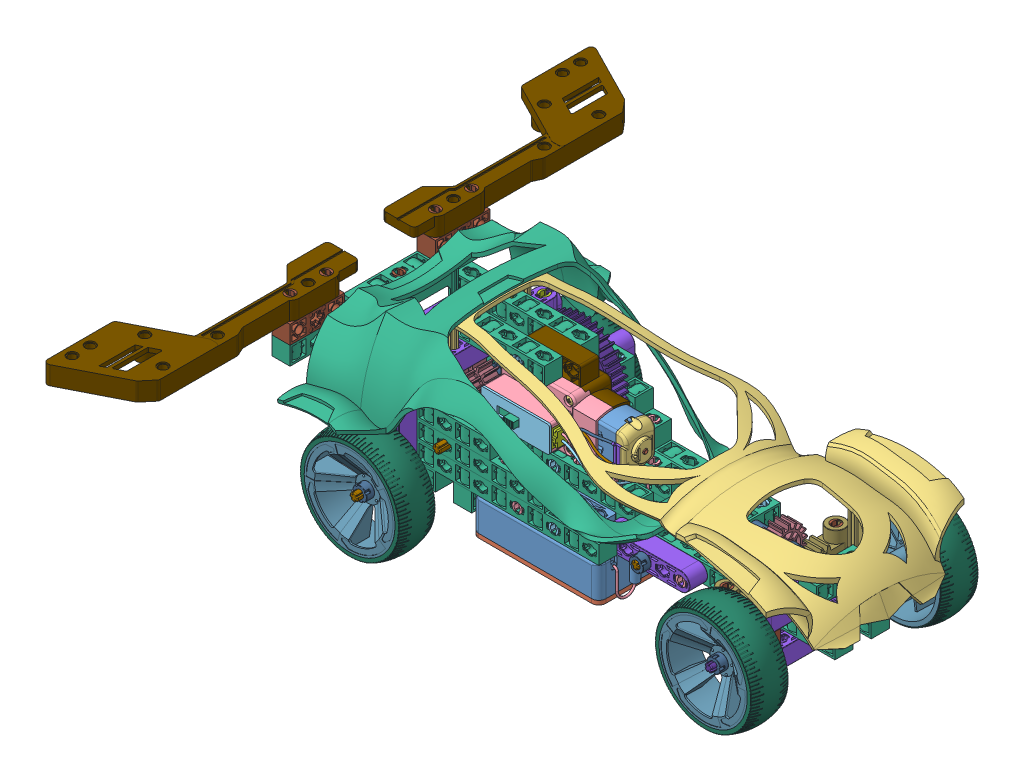
SolidWorks assembly Montagem Carro completo 2, configuration Default. Lengths in mm.
Overall size (284.9 101.61 271.25).
192 component instances, 42 part files, 28 mates.
Components (placement in the parent):
- Subconjunto Vigas traseiras-1: Subconjunto Vigas traseiras [Default] at (83.2647 104.1933 53.5414) x (-1 0 0) z (0 0 1) size (139.81 64.5 81)
  - Subconjunto caixa pilhas-1: Subconjunto caixa pilhas [Default] at (12.3707 2.7009 -5.3452) size (69.81 28.5 63)
    - Caixa das pilhas-1: Caixa das pilhas [Default] at (12.7241 32.9375 62.5857) size (69.5 28.5 63)
    - Tampa compartimento das pilhas-1: Tampa compartimento das pilhas [Default] at (12.7241 42.9375 62.5857) x (0 0 1) z (1 0 0) size (63 4 69.5)
    - pan head cross recess screw_iso-4: pan head cross recess screw_iso [ISO 7045 - M2 x 6 - Z - 6N] at (-20.7759 42.7775 62.5857) x (0 -1 0) z (0.784317 0 0.62036) size (7.57 4 4)
  - Pino Paralelo-2: Pino Paralelo [Default] at (34.0948 23.1383 79.7405) x (-1 0 0) z (0 -1 0) size (6 18 4.58)
  - Pino Triplo Longo-1: Pino Triplo Longo [Default] at (16.0948 23.1383 75.2405) x (1 0 0) z (0 -1 0) size (6 27 4.58)
  - Viga alternada-1: Viga alternada [Viga alternada de 15] at (61.0948 23.1383 84.2405) x (1 0 0) z (0 1 0) size (135 9 9)
  - Pino Triplo Longo-2: Pino Triplo Longo [Default] at (97.0948 23.1383 84.2405) size (6 27 4.58)
  - Pino Triplo Longo-3: Pino Triplo Longo [Default] at (79.0948 23.1383 84.2405) size (6 27 4.58)
  - Viga alternada-2: Viga alternada [Viga alternada de 3] at (88.0948 32.1383 84.2405) size (27 9 9)
  - Pino Perpendicular-1: Pino Perpendicular [Default] at (61.0948 27.6383 84.2405) x (0 0 -1) z (1 0 0) size (6 18 6)
  - Viga alternada-3: Viga alternada [Viga alternada de 11] at (70.0948 14.1383 84.2405) size (99 9 9)
  - Pino Paralelo-4: Pino Paralelo [Default] at (43.0948 18.6383 84.2405) size (6 18 4.58)
  - Pino Paralelo-5: Pino Paralelo [Default] at (25.0948 18.6383 84.2405) size (6 18 4.58)
  - Pino Paralelo-6: Pino Paralelo [Default] at (34.0948 23.1383 34.7405) x (-1 0 0) z (0 1 0) size (6 18 4.58)
  - Pino Triplo Longo-4: Pino Triplo Longo [Default] at (16.0948 23.1383 39.2405) x (1 0 0) z (0 1 0) size (6 27 4.58)
  - Viga alternada-4: Viga alternada [Viga alternada de 15] at (61.0948 23.1383 30.2405) x (1 0 0) z (0 -1 0) size (135 9 9)
  - Pino Triplo Longo-5: Pino Triplo Longo [Default] at (97.0948 23.1383 30.2405) size (6 27 4.58)
  - Pino Triplo Longo-6: Pino Triplo Longo [Default] at (79.0948 23.1383 30.2405) size (6 27 4.58)
  - Viga alternada-5: Viga alternada [Viga alternada de 3] at (88.0948 32.1383 30.2405) size (27 9 9)
  - Pino Perpendicular-2: Pino Perpendicular [Default] at (61.0948 27.6383 30.2405) x (0 0 1) z (-1 0 0) size (6 18 6)
  - Viga alternada-6: Viga alternada [Viga alternada de 11] at (70.0948 14.1383 30.2405) size (99 9 9)
  - Pino Paralelo-7: Pino Paralelo [Default] at (25.0948 18.6383 30.2405) size (6 18 4.58)
  - Pino Perpendicular-3: Pino Perpendicular [Default] at (115.0948 27.6383 84.2405) x (0 0 1) z (-1 0 0) size (6 18 6)
  - Pino Perpendicular-4: Pino Perpendicular [Default] at (115.0948 9.6383 84.2405) size (6 18 6)
  - Pino Perpendicular-5: Pino Perpendicular [Default] at (115.0948 27.6383 30.2405) x (0 0 -1) z (1 0 0) size (6 18 6)
  - Pino Perpendicular-6: Pino Perpendicular [Default] at (115.0948 9.6383 30.2405) size (6 18 6)
  - Viga alternada-7: Viga alternada [Viga alternada de 7] at (61.0948 32.1383 57.2405) x (0 0 -1) z (1 0 0) size (63 9 9)
  - Viga plana-1: Viga plana [Viga plana de 7] at (115.0948 32.1383 57.2405) x (0 0 1) z (-1 0 0) size (63 9 9)
  - Viga plana-2: Viga plana [Viga plana de 7] at (115.0948 5.1383 57.2405) x (0 0 1) z (1 0 0) size (63 9 9)
  - Pino Paralelo-8: Pino Paralelo [Default] at (61.0948 9.6383 84.2405) size (6 18 4.58)
  - Viga alternada-8: Viga alternada [Viga alternada de 7] at (79.0948 5.1383 84.2405) x (1 0 0) z (0 -1 0) size (63 9 9)
  - Pino Paralelo-9: Pino Paralelo [Default] at (97.0948 0.6383 84.2405) x (-1 0 0) z (0 0 -1) size (6 18 4.58)
  - Pino Triplo Longo-7: Pino Triplo Longo [Default] at (79.0948 -3.8617 84.2405) x (-1 0 0) z (0 0 -1) size (6 27 4.58)
  - Viga alternada-9: Viga alternada [Viga alternada de 5] at (97.0948 -3.8617 84.2405) size (45 9 9)
  - Viga alternada-10: Viga alternada [Viga alternada de 9] at (70.0948 5.1383 30.2405) x (1 0 0) z (0 1 0) size (81 9 9)
  - Viga alternada-11: Viga alternada [Viga alternada de 9] at (79.0948 -3.8617 30.2405) size (81 9 9)
  - Pino Triplo Longo-8: Pino Triplo Longo [Default] at (61.0948 5.1383 30.2405) x (-1 0 0) z (0 0 1) size (6 27 4.58)
  - Pino Triplo Longo-9: Pino Triplo Longo [Default] at (43.0948 5.1383 30.2405) x (1 0 0) z (0 0 -1) size (6 27 4.58)
  - Pino Paralelo-10: Pino Paralelo [Default] at (97.0948 0.6383 30.2405) size (6 18 4.58)
  - Pino Perpendicular-8: Pino Perpendicular [Default] at (79.0948 -8.3617 30.2405) size (6 18 6)
  - Viga plana-3: Viga plana [Viga plana de 5] at (88.0948 14.1383 93.2405) x (0 -1 0) z (-1 0 0) size (45 9 9)
  - Pino Perpendicular-9: Pino Perpendicular [Default] at (88.0948 -3.8617 88.7405) x (0 -1 0) z (-1 0 0) size (6 18 6)
  - Viga plana-5: Viga plana [Viga plana de 7] at (79.0948 -12.8617 57.2405) x (0 0 1) z (-1 0 0) size (63 9 9)
  - Viga alternada-12: Viga alternada [Viga alternada de 3 (Preta)] at (106.0948 5.1383 75.2405) x (0 -1 0) z (1 0 0) size (27 9 9)
  - Pino Perpendicular-11: Pino Perpendicular [Default] at (106.0948 -3.8617 79.7405) x (0 -1 0) z (1 0 0) size (6 18 6)
  - Pino Perpendicular-12: Pino Perpendicular [Default] at (106.0948 14.1383 79.7405) x (0 -1 0) z (1 0 0) size (6 18 6)
  - Pino Perpendicular-13: Pino Perpendicular [Default] at (88.0948 -3.8617 25.7405) x (0 -1 0) z (1 0 0) size (6 18 6)
  - Viga plana-6: Viga plana [Viga plana de 5] at (88.0948 14.1383 21.2405) x (0 -1 0) z (1 0 0) size (45 9 9)
  - Pino Perpendicular-15: Pino Perpendicular [Default] at (106.0948 -3.8617 34.7405) x (0 -1 0) z (-1 0 0) size (6 18 6)
  - Viga alternada-13: Viga alternada [Viga alternada de 3 (Preta)] at (106.0948 5.1383 39.2405) x (0 -1 0) z (-1 0 0) size (27 9 9)
  - Pino Perpendicular-16: Pino Perpendicular [Default] at (106.0948 14.1383 34.7405) x (0 -1 0) z (-1 0 0) size (6 18 6)
  - Viga plana-7: Viga plana [Viga plana de 3] at (52.0948 5.1383 21.2405) x (0 1 0) z (-1 0 0) size (27 9 9)
  - Pino Perpendicular-17: Pino Perpendicular [Default] at (52.0948 14.1383 25.7405) x (0 1 0) z (-1 0 0) size (6 18 6)
  - Pino Perpendicular-18: Pino Perpendicular [Default] at (52.0948 5.1383 25.7405) x (0 1 0) z (-1 0 0) size (6 18 6)
  - Pino Perpendicular-19: Pino Perpendicular [Default] at (88.0948 23.1383 88.7405) x (1 0 0) z (0 1 0) size (6 18 6)
  - Pino Perpendicular-20: Pino Perpendicular [Default] at (88.0948 23.1383 25.7405) x (1 0 0) z (0 -1 0) size (6 18 6)
- Subconjunto direção-1: Subconjunto direção [Default] at (103.1154 2.655 4.4947) size (149.73 73.54 113.05) (flexible)
  - Viga alternada-1: Viga alternada [Viga alternada de 15] at (18.0545 78.4 115.2872) size (135 9 9)
  - Viga alternada-2: Viga alternada [Viga alternada de 15] at (18.0545 78.4 97.2872) size (135 9 9)
  - Viga plana-2: Viga plana [Viga plana de 5] at (0.0545 78.4 124.2872) x (1 0 0) z (0 1 0) size (45 9 9)
  - Pino Paralelo-1: Pino Paralelo [Default] at (18.0545 78.4 119.7872) x (1 0 0) z (0 1 0) size (6 18 4.58)
  - Veio-1: Veio [Veio no meio] at (0.0545 78.4 79.2872) x (0.200907 0.97961 0) z (0 0 1) size (4 4 54)
  - Freio-1: Freio [Freio Pequeno] at (0.0545 78.4 132.7872) x (0.97961 -0.200907 0) z (0 0 -1) size (7 7 4.02)
  - Viga plana-3: Viga plana [Viga plana de 3] at (0.0545 78.4 106.2872) x (1 0 0) z (0 -1 0) size (27 9 9)
  - Viga plana-4: Viga plana [Viga plana de 5] at (0.0545 78.4 88.2872) x (-1 0 0) z (0 1 0) size (45 9 9)
  - Freio-2: Freio [Freio Pequeno] at (0.0545 78.4 79.7872) x (-0.97961 0.200907 0) z (0 0 1) size (7 7 4.02)
  - Pino Paralelo-2: Pino Paralelo [Default] at (18.0545 78.4 92.7872) x (1 0 0) z (0 1 0) size (6 18 4.58)
  - Viga plana-5: Viga plana [Viga plana de 3] at (27.0545 87.4 106.2872) x (0 0 1) z (-1 0 0) size (27 9 9)
  - Pino Triplo Longo-1: Pino Triplo Longo [Default] at (27.0545 87.4 97.2872) x (0 0 1) z (-1 0 0) size (6 27 4.58)
  - Pino Triplo Longo-3: Pino Triplo Longo [Default] at (27.0545 87.4 115.2872) x (0 0 1) z (-1 0 0) size (6 27 4.58)
  - Viga alternada-3: Viga alternada [Viga alternada de 3] at (27.0545 96.4 106.2872) x (0 0 1) z (-1 0 0) size (27 9 9)
  - Pino Triplo Longo-4: Pino Triplo Longo [Default] at (63.0545 78.4 97.2872) size (6 27 4.58)
  - Pino Triplo Longo-5: Pino Triplo Longo [Default] at (63.0545 78.4 115.2872) size (6 27 4.58)
  - Viga plana-6: Viga plana [Viga plana de 7] at (63.0545 69.4 106.2872) x (0 0 -1) z (1 0 0) size (63 9 9)
  - Viga com pinos-1: Viga com pinos [Viga com pinos (Cinzenta)] at (54.0581 78.4 79.0329) x (0.999601 0 0.02826) z (-0.02826 0 0.999601) size (27 27 9)
  - Viga com pinos-2: Viga com pinos [Viga com pinos (Cinzenta)] at (54.0581 78.4 133.0329) x (0.999601 0 0.02826) z (-0.02826 0 0.999601) size (27 27 9)
  - Haste dentada-2: Haste dentada [Default] at (45.0617 85.9 105.7785) x (0 0 1) z (-1 0 0) size (63 9 9)
  - Freio-4: Freio [Freio Pequeno] at (62.8143 78.4 141.7838) x (0.706725 0.707206 0.01998) z (0.02826 0 -0.999601) size (7 7 4.02)
  - Pino Paralelo-3: Pino Paralelo [Default] at (81.0545 82.9 115.2872) size (6 18 4.58)
  - Viga plana-7: Viga plana [Viga em L] at (72.0545 87.4 115.2872) size (27 9 27)
  - Freio-6: Freio [Freio Pequeno] at (63.2947 78.4 70.7906) x (-0.609265 0.79278 -0.017224) z (-0.02826 0 0.999601) size (7 7 4.02)
  - Pino Paralelo-4: Pino Paralelo [Default] at (81.0545 82.9 97.2872) size (6 18 4.58)
  - Viga plana-8: Viga plana [Viga em L] at (72.0545 87.4 97.2872) x (1 0 0) z (0 0 -1) size (27 9 27)
  - Pino Perpendicular-2: Pino Perpendicular [Default] at (72.0545 91.9 115.2872) x (0 0 1) z (-1 0 0) size (6 18 6)
  - Pino Perpendicular-3: Pino Perpendicular [Default] at (72.0545 91.9 97.2872) x (0 0 1) z (-1 0 0) size (6 18 6)
  - Viga alternada-4: Viga alternada [Viga alternada de 3] at (72.0545 96.4 106.2872) x (0 0 1) z (-1 0 0) size (27 9 9)
  - Veio-4: Veio [Veio Direção] at (81.0545 96.4 106.2872) x (0 0.998403 0.056489) z (-1 0 0) size (4 4 72)
  - Freio-7: Freio [Frei Grande] at (40.5545 96.4 106.2872) x (0 -0.998403 -0.056489) z (-1 0 0) size (7 7 9.02)
  - Roda Dentada 18-1: Roda Dentada 18 [Default] at (45.0545 96.4 106.2872) x (0 -0.998403 -0.056489) z (1 0 0) size (19.8 20 9)
  - Freio-8: Freio [Freio Pequeno] at (18.5545 96.4 106.2872) x (0 -0.056489 0.998403) z (1 0 0) size (7 7 4.02)
  - Freio-10: Freio [Freio Pequeno] at (80.5545 96.4 106.2872) x (0 0.056489 -0.998403) z (-1 0 0) size (7 7 4.02)
  - Subconjunto Rodas-1: Subconjunto Rodas [Default] at (112.9706 74.3889 157.6368) x (0.02826 0 -0.999601) z (-0.706923 0.707008 -0.019985) size (20 52.21 52.21)
    - Jante (centro arredondado)-1: Jante (centro arredondado) [Default] at (3.4293 32.9268 38.6094) size (20 48 48)
    - Pneu com detalhes-1: Pneu com detalhes [Default] at (3.4293 32.9268 38.6094) x (1 0 0) z (0 0.004073 0.999992) size (18 52 52)
  - Volante-3: Volante [Default] at (18.5545 96.4 106.2872) x (0 -0.056489 0.998403) z (-1 0 0) size (26 17 5.56)
  - Subconjunto Rodas-2: Subconjunto Rodas [Default] at (114.3601 75.829 57.7993) x (-0.02826 0 0.999601) z (-0.792463 -0.609508 -0.022404) size (20 52.21 52.21)
    - Jante (centro arredondado)-1: Jante (centro arredondado) [Default] at (3.4293 32.9268 38.6094) size (20 48 48)
    - Pneu com detalhes-1: Pneu com detalhes [Default] at (3.4293 32.9268 38.6094) x (1 0 0) z (0 0.004073 0.999992) size (18 52 52)
  - Freio-11: Freio [Freio Pequeno] at (62.3904 78.4 156.7778) x (0.706725 0.707206 0.01998) z (0.02826 0 -0.999601) size (7 7 4.02)
  - Freio-12: Freio [Freio Pequeno] at (63.7186 78.4 55.7966) x (0.609265 -0.79278 0.017224) z (-0.02826 0 0.999601) size (7 7 4.02)
  - Veio de direção-1: Veio de direção [Default] at (62.9414 78.4 137.2856) x (0.706923 -0.707008 0.019985) z (-0.706725 -0.707206 -0.01998) size (5 31 5)
  - Veio de direção-2: Veio de direção [Default] at (63.1675 78.4 75.2888) x (-0.792463 -0.609508 -0.022404) z (0.609265 -0.79278 0.017224) size (5 31 5)
  - Freio-13: Freio [Freio Pequeno] at (53.5545 96.4 106.2872) x (0 0.056489 -0.998403) z (-1 0 0) size (7 7 4.02)
- Subconjunto motor (+ vigas pinos engrenagem)-1: Subconjunto motor (+ vigas pinos engrenagem) [Default] at (30.8311 154.6885 76.1191) x (1 0 0) z (0 -1 0) size (90 66.4 56.53) (flexible)
  - Subconjunto motor-1: Subconjunto motor [Default] at (-5.6196 12.0173 6.5738) size (65.27 37.9 45) (flexible)
    - Caixa motor superior-1: Caixa motor superior [Default] at (12.9584 20.6455 40.0597) size (48 14.5 45)
    - Carcaça-1: Carcaça [Default] at (41.4584 25.1455 40.0597) size (21 15 20.02)
    - Veio rotor-1: Veio rotor [Default] at (40.9584 25.1455 40.0597) x (1 0 0) z (0 -0.841943 0.539566) size (36 2 2)
    - Tampa-1: Tampa [Default] at (52.4584 25.1455 40.0597) x (-1 0 0) z (0 0 -1) size (10.02 16 20.34)
    - Caixa motor inferior-1: Caixa motor inferior [Default] at (12.9584 33.1455 40.0597) x (1 0 0) z (0 0 -1) size (48 22 27)
    - Capa interruptor-1: Capa interruptor [Default] at (12.9584 43.1455 40.0597) size (34 8 13)
    - Interruptor-1: Interruptor [Default] at (12.4584 42.1455 40.0597) size (18 5 6)
    - pan head cross recess screw_iso-1: pan head cross recess screw_iso [ISO 7045 - M2 x 12 - Z - 12N] at (-2.5416 32.9855 50.5597) x (0 -1 0) z (0 0 1) size (13.57 4 4)
    - pan head cross recess screw_iso-2: pan head cross recess screw_iso [ISO 7045 - M2 x 12 - Z - 12N] at (28.4584 32.9855 50.5597) x (0 -1 0) z (-0.094826 0 0.995494) size (13.57 4 4)
    - pan head cross recess screw_iso-3: pan head cross recess screw_iso [ISO 7045 - M2 x 12 - Z - 12N] at (28.4584 32.9855 29.5597) x (0 -1 0) z (0 0 1) size (13.57 4 4)
    - pan head cross recess screw_iso-4: pan head cross recess screw_iso [ISO 7045 - M2 x 12 - Z - 12N] at (-2.5416 32.9855 29.5597) x (0 -1 0) z (0 0 1) size (13.57 4 4)
    - Ficha-1: Ficha [Default] at (31.9584 39.6455 40.0597) x (-1 0 0) z (0 0 -1) size (9 7 9)
    - Terminais motor-1: Terminais motor [Default] at (52.9584 32.7705 40.0597) size (3 2.95 10.2)
    - Part14^Subconjunto motor-1: Part14^Subconjunto motor [Default] at (27.9584 33.1455 40.0597) x (0 0 1) z (1 0 0) size (7.51 1.91 24.5) (virtual)
    - Part15^Subconjunto motor-1: Part15^Subconjunto motor [Default] at (27.9584 33.1455 40.0597) x (0 0 1) z (1 0 0) size (7.38 2.7 24.5) (virtual)
    - Veios interiores motor-1: Veios interiores motor [Veio cilindro menor] at (16.9584 22.6455 40.0597) x (0 1 0) z (0.959634 0 0.281251) size (19 2 2)
    - Veios interiores motor-2: Veios interiores motor [Veio cilindro maior] at (5.9584 24.6955 40.0597) x (0 1 0) z (0 0 1) size (14.9 2 2)
    - Engrenagem veio rotor-1: Engrenagem veio rotor [Default] at (25.6584 25.1455 40.0597) x (0 0.753099 0.657907) z (0 -0.657907 0.753099) size (6 5.02 6.03)
    - 1º Engrenagem-1: 1º Engrenagem [Default] at (16.9584 29.7455 40.0597) x (0.999602 0 0.028216) z (0.028216 0 -0.999602) size (17.01 7.3 17.01)
    - 2º e 3º Engrenagem-1: 2º e 3º Engrenagem [Default] at (5.9584 25.7455 40.0597) x (-0.546136 0 0.837696) z (0.837696 0 0.546136) size (17.4 6.4 17.38)
    - 2º e 3º Engrenagem-2: 2º e 3º Engrenagem [Default] at (16.9584 22.0455 40.0597) x (-0.894705 0 0.446658) z (0.446658 0 0.894705) size (17.4 6.4 17.38)
    - 4º Engrenagem-1: 4º Engrenagem [Default] at (5.9584 19.7455 40.0597) x (-0.755862 0 0.65473) z (0.65473 0 0.755862) size (17.4 3 17.4)
    - Engrenagem saída do motor-1: Engrenagem saída do motor [Default] at (5.9584 18.2455 40.0597) x (-0.983161 0 -0.182739) z (-0.182739 0 0.983161) size (11.75 9 11.02)
  - Pino Triplo Longo-1: Pino Triplo Longo [Default] at (0.3388 34.6628 64.6335) x (-1 0 0) z (0 0 1) size (6 27 4.58)
  - Pino Triplo Longo-2: Pino Triplo Longo [Default] at (18.3388 34.6628 64.6335) x (-1 0 0) z (0 0 1) size (6 27 4.58)
  - Pino Triplo Longo-3: Pino Triplo Longo [Default] at (0.3388 34.6628 28.6335) size (6 27 4.58)
  - Viga alternada-1: Viga alternada [Viga alternada de 5] at (-8.6612 43.6628 28.6335) x (1 0 0) z (0 -1 0) size (45 9 9)
  - Viga alternada-2: Viga alternada [Viga alternada de 7] at (27.3388 43.6628 64.6335) size (63 9 9)
  - Pino Perpendicular-1: Pino Perpendicular [Default] at (-26.6612 43.6628 33.1335) x (0 -1 0) z (1 0 0) size (6 18 6)
  - Pino Paralelo-1: Pino Paralelo [Default] at (45.3388 43.6628 69.1335) x (1 0 0) z (0 1 0) size (6 18 4.58)
  - Pino Paralelo-2: Pino Paralelo [Default] at (27.3388 43.6628 69.1335) x (1 0 0) z (0 1 0) size (6 18 4.58)
  - Viga alternada-3: Viga alternada [Viga alternada de 5] at (-8.6612 25.6628 28.6335) x (1 0 0) z (0 -1 0) size (45 9 9)
  - Pino Perpendicular-2: Pino Perpendicular [Default] at (-26.6612 25.6628 33.1335) x (0 1 0) z (-1 0 0) size (6 18 6)
  - Viga alternada-4: Viga alternada [Viga alternada de 7] at (27.3388 25.6628 64.6335) x (1 0 0) z (0 0 -1) size (63 9 9)
  - Pino Paralelo-3: Pino Paralelo [Default] at (27.3388 25.6628 69.1335) x (1 0 0) z (0 1 0) size (6 18 4.58)
  - Pino Paralelo-4: Pino Paralelo [Default] at (45.3388 25.6628 69.1335) x (1 0 0) z (0 1 0) size (6 18 4.58)
  - Veio-1: Veio [Veio do motor] at (0.3388 -7.2372 46.6335) x (-0.983161 0 -0.182739) z (0 1 0) size (4 4 36)
  - Roda Dentada 41-1: Roda Dentada 41 [Default] at (0.3388 17.6628 46.6335) x (-0.983161 0 -0.182739) z (0 1 0) size (42.99 42.96 10)
- Subconjunto Aileron-1: Subconjunto Aileron [Default] at (26.7336 51.1658 81.6411) x (0 0 1) z (-1 0 0) size (271.25 45.1 54)
  - Viga alternada-1: Viga alternada [Viga alternada de 11 (Preta)] at (29.1408 56.8892 76.5637) size (99 9 9)
  - Viga com pinos-2: Viga com pinos [Viga com pinos (Cinzenta)] at (65.1408 65.8892 76.5637) size (27 27 9)
  - Viga com pinos-3: Viga com pinos [Viga com pinos (Branca)] at (29.1408 47.8892 76.5637) size (27 27 9)
  - Viga alternada-2: Viga alternada [Viga alternada de 3 (Preta)] at (38.1408 38.8892 67.5637) x (0 0 -1) z (-1 0 0) size (27 9 9)
  - Pino Perpendicular-1: Pino Perpendicular [Default] at (38.1408 43.3892 58.5637) x (-1 0 0) z (0 0 1) size (6 18 6)
  - Asa-3: Asa [Asa Direita] at (65.1408 79.3892 76.5637) x (-1 0 0) z (0 0 1) size (122.12 9.1 36.5)
  - Viga com pinos-6: Viga com pinos [Viga com pinos (Cinzenta)] at (-6.8592 65.8892 76.5637) x (-1 0 0) z (0 0 -1) size (27 27 9)
  - Viga alternada-4: Viga alternada [Viga alternada de 3 (Preta)] at (20.1408 38.8892 67.5637) x (0 0 -1) z (-1 0 0) size (27 9 9)
  - Asa-5: Asa [Asa Esquerda] at (38.1408 79.3892 76.5637) x (-1 0 0) z (0 0 1) size (122.12 9.1 36.5)
  - Pino Perpendicular-3: Pino Perpendicular [Default] at (20.1408 43.3892 58.5637) x (1 0 0) z (0 0 -1) size (6 18 6)
- Subconjunto 1º aumento-1: Subconjunto 1º aumento [Default] at (10.181 89.2697 93.6538) x (-0.111043 -0.993816 0) z (0 0 1) size (27.87 28 72) (flexible)
  - Veio-1: Veio [Veio Direção] at (-1.1123 2.8833 -19.3719) size (4 4 72)
  - Roda Dentada 10-1: Roda Dentada 10 [Default] at (-1.1123 2.8833 -0.8719) size (11.6 12 9)
  - Roda Dentada 26-2: Roda Dentada 26 [Default] at (-1.1123 2.8833 34.1281) size (27.87 28 9)
  - Freio-1: Freio [Freio Pequeno] at (-1.1123 2.8833 12.6281) size (7 7 4.02)
  - Freio-2: Freio [Freio Pequeno] at (-1.1123 2.8833 20.6281) x (1 0 0) z (0 0 -1) size (7 7 4.02)
  - Freio-3: Freio [Frei Grande] at (-1.1123 2.8833 20.6281) size (7 7 9.02)
  - Freio-4: Freio [Frei Grande] at (-1.1123 2.8833 12.6281) x (-1 0 0) z (0 0 -1) size (7 7 9.02)
- Subconjunto 2º aumento-2: Subconjunto 2º aumento [Default] at (-5.1688 93.2831 88.3144) x (-0.561891 0.827211 0) z (0 0 1) size (19.8 20 81) (flexible)
  - Veio-1: Veio [Veio 2º aumento] at (-2.8606 1.5336 -17.5324) size (4 4 81)
  - Roda Dentada 10-1: Roda Dentada 10 [Default] at (-2.8606 1.5336 40.4676) size (11.6 12 9)
  - Freio-1: Freio [Freio Pequeno] at (-2.8606 1.5336 35.9676) x (-1 0 0) z (0 0 -1) size (7 7 4.02)
  - Roda Dentada 18-1: Roda Dentada 18 [Default] at (-2.8606 1.5336 27.4676) size (19.8 20 9)
  - Roda Dentada 18-2: Roda Dentada 18 [Default] at (-2.8606 1.5336 18.4676) size (19.8 20 9)
  - Freio-2: Freio [Freio Pequeno] at (-2.8606 1.5336 9.9676) size (7 7 4.02)
  - Freio-4: Freio [Frei Grande] at (-2.8606 1.5336 9.9676) x (-1 0 0) z (0 0 -1) size (7 7 9.02)
- Subconjunto Veio final-1: Subconjunto Veio final [Default] at (50.8445 119.9269 8.5329) x (-0.969875 0.243603 0) z (0 0 1) size (52.21 52.21 121) (flexible)
  - Veio-1: Veio [Veio Final] at (42.3357 59.9923 43.749) size (4 4 117)
  - Roda Dentada 18-1: Roda Dentada 18 [Default] at (42.3357 59.9923 106.749) size (19.8 20 9)
  - Roda Dentada 18-2: Roda Dentada 18 [Default] at (42.3357 59.9923 97.749) size (19.8 20 9)
  - Freio-1: Freio [Frei Grande] at (42.3357 59.9923 89.249) x (-1 0 0) z (0 0 -1) size (7 7 9.02)
  - Freio-2: Freio [Frei Grande] at (42.3357 59.9923 115.249) size (7 7 9.02)
  - Freio-3: Freio [Freio Pequeno] at (42.3357 59.9923 89.249) size (7 7 4.02)
  - Freio-4: Freio [Freio Pequeno] at (42.3357 59.9923 115.249) x (-1 0 0) z (0 0 -1) size (7 7 4.02)
  - Freio-5: Freio [Freio Pequeno] at (42.3357 59.9923 46.749) size (7 7 4.02)
  - Subconjunto Rodas-1: Subconjunto Rodas [Default] at (80.9451 27.0654 47.3198) x (0 0 1) z (-1 0 0) size (20 52.21 52.21)
    - Jante (centro arredondado)-1: Jante (centro arredondado) [Default] at (3.4293 32.9268 38.6094) size (20 48 48)
    - Pneu com detalhes-1: Pneu com detalhes [Default] at (3.4293 32.9268 38.6094) x (1 0 0) z (0 0.004073 0.999992) size (18 52 52)
  - Subconjunto Rodas-3: Subconjunto Rodas [Default] at (3.7263 27.0654 157.1783) x (0 0 -1) z (1 0 0) size (20 52.21 52.21)
    - Jante (centro arredondado)-1: Jante (centro arredondado) [Default] at (3.4293 32.9268 38.6094) size (20 48 48)
    - Pneu com detalhes-1: Pneu com detalhes [Default] at (3.4293 32.9268 38.6094) x (1 0 0) z (0 0.004073 0.999992) size (18 52 52)
  - Freio-9: Freio [Freio Pequeno] at (42.3357 59.9923 157.749) x (-1 0 0) z (0 0 -1) size (7 7 4.02)
- Carroçaria parte comprida-1: Carroçaria parte comprida [Default] at (4.1699 113.3206 110.782) size (202.22 51.99 99.26)
- Part2^Montagem Carro completo-1: Part2^Montagem Carro completo [Default] at (88.3699 68.555 110.782) x (0 0 1) z (1 0 0) size (23.89 52.5 35.5)
- Part3^Montagem Carro completo-1: Part3^Montagem Carro completo [Default] at (56.1699 108.055 127.782) x (0 1 0) z (1 0 0) size (49.52 46.13 35.5)
- Carroçaria parte curta-1: Carroçaria parte curta [Default] at (4.1699 137.8495 110.782) size (140.2 59.94 138.22)
Mates (geometry in assembly coordinates):
- Concentric31: concentric aligned: cylinder of Subconjunto Vigas traseiras-1/Pino Triplo Longo-1 through (67.1699 81.055 142.282) axis (0 0 1) radius 2; cylinder of Subconjunto direção-1/Viga alternada-1 through (67.1699 81.055 115.282) axis (0 0 1) radius 2
- Coincident51: coincident: line of Subconjunto Vigas traseiras-1/Subconjunto caixa pilhas-1/Caixa das pilhas-1 through (76.1699 85.555 96.282) axis (-1 0 0); plane of Subconjunto direção-1/Viga alternada-2 through (121.1699 85.555 101.782) normal (0 1 0)
- Coincident61: coincident anti-aligned: plane of Subconjunto Vigas traseiras-1/Subconjunto caixa pilhas-1/Caixa das pilhas-1 through (80.6699 85.555 97.282) normal (0 0 1); plane of Subconjunto direção-1/Viga alternada-2 through (53.6699 85.555 97.282) normal (0 0 -1)
- Concentric41: concentric aligned: cylinder of Subconjunto direção-1/Viga alternada-2 through (76.1699 76.555 101.782) axis (0 1 0) radius 2; cylinder of Subconjunto motor (+ vigas pinos engrenagem)-1/Pino Paralelo-4 through (76.1699 94.555 101.782) axis (0 1 0) radius 2
- Concentric51: concentric aligned: cylinder of Subconjunto direção-1/Viga alternada-1 through (76.1699 76.555 119.782) axis (0 1 0) radius 2; cylinder of Subconjunto motor (+ vigas pinos engrenagem)-1/Pino Paralelo-1 through (76.1699 94.555 119.782) axis (0 1 0) radius 2
- Coincident71: coincident anti-aligned: plane of Subconjunto direção-1/Viga alternada-1 through (121.1699 85.555 119.782) normal (0 1 0); plane of Subconjunto motor (+ vigas pinos engrenagem)-1/Viga alternada-2 through (26.6699 85.555 124.282) normal (0 -1 0)
- Concentric61: concentric anti-aligned: cylinder of Subconjunto Vigas traseiras-1/Viga plana-2 through (-31.8301 94.555 119.782) axis (0 1 0) radius 2; cylinder of Subconjunto Aileron-1/Pino Perpendicular-1 through (-31.8301 85.555 119.782) axis (0 -1 0) radius 2
- Concentric71: concentric anti-aligned: cylinder of Subconjunto Vigas traseiras-1/Viga plana-2 through (-31.8301 94.555 101.782) axis (0 1 0) radius 2; cylinder of Subconjunto Aileron-1/Pino Perpendicular-3 through (-31.8301 85.555 101.782) axis (0 -1 0) radius 2
- Coincident81: coincident anti-aligned: plane of Subconjunto Vigas traseiras-1/Viga plana-2 through (-31.8301 94.555 83.782) normal (0 -1 0); plane of Subconjunto Aileron-1/Viga alternada-2 through (-40.8301 94.555 119.782) normal (0 1 0)
- Concentric81: concentric anti-aligned: cylinder of Subconjunto Vigas traseiras-1/Viga alternada-6 through (13.1699 90.055 79.282) axis (0 0 1) radius 2; cylinder of Subconjunto 1º aumento-1/Veio-1 through (13.1699 90.055 146.282) axis (0 0 -1) radius 2
- GearMate3: gear = 41 : 10 mm: cylinder of Subconjunto 1º aumento-1/Roda Dentada 10-1 through (13.1699 90.055 97.282) axis (0 0 -1) radius 3.5; cylinder of Subconjunto motor (+ vigas pinos engrenagem)-1/Roda Dentada 41-1 through (31.1699 108.055 97.282) axis (0 0 -1) radius 19
- Coincident82: coincident anti-aligned: plane of Subconjunto Vigas traseiras-1/Viga alternada-6 through (62.6699 85.555 88.282) normal (0 0 1); plane of Subconjunto 1º aumento-1/Roda Dentada 10-1 through (13.1699 90.055 88.282) normal (0 0 -1)
- Concentric82: concentric anti-aligned: cylinder of Subconjunto Vigas traseiras-1/Viga plana-3 through (-4.8301 90.055 142.282) axis (0 0 1) radius 2; cylinder of Subconjunto 2º aumento-2/Veio-1 through (-4.8301 90.055 151.782) axis (0 0 -1) radius 2
- Coincident83: coincident anti-aligned: plane of Subconjunto Vigas traseiras-1/Viga alternada-3 through (62.6699 85.555 133.282) normal (0 0 -1); plane of Subconjunto 2º aumento-2/Roda Dentada 10-1 through (-4.8301 90.055 133.282) normal (0 0 1)
- GearMate4: gear = 10 : 26 mm: cylinder of Subconjunto 1º aumento-1/Roda Dentada 26-2 through (13.1699 90.055 131.282) axis (0 0 -1) radius 11.5; cylinder of Subconjunto 2º aumento-2/Roda Dentada 10-1 through (-4.8301 90.055 133.282) axis (0 0 -1) radius 3.5
- Concentric83: concentric aligned: cylinder of Subconjunto Vigas traseiras-1/Viga plana-6 through (-4.8301 72.055 79.282) axis (0 0 -1) radius 2; cylinder of Subconjunto Veio final-1/Veio-1 through (-4.8301 72.055 169.282) axis (0 0 -1) radius 2
- Coincident84: coincident anti-aligned: plane of Subconjunto Vigas traseiras-1/Viga plana-3 through (-4.8301 72.055 151.282) normal (0 0 1); plane of Subconjunto Veio final-1/Subconjunto Rodas-3/Jante (centro arredondado)-1 through (-4.8301 72.055 151.282) normal (0 0 -1)
- GearMate5: gear = 18 : 18 mm: cylinder of Subconjunto Veio final-1/Roda Dentada 18-2 through (-4.8301 72.055 109.782) axis (0 0 -1) radius 7.5; cylinder of Subconjunto 2º aumento-2/Roda Dentada 18-2 through (-4.8301 90.055 110.282) axis (0 0 -1) radius 7.5
- Concentric84: concentric anti-aligned: cylinder of Subconjunto Vigas traseiras-1/Viga plana-5 through (4.1699 121.555 92.782) axis (0 -1 0) radius 2; cylinder of Carroçaria parte comprida-1 through (4.1699 113.3206 92.782) axis (0 1 0) radius 1.35
- Concentric85: concentric aligned: cylinder of Subconjunto direção-1/Viga plana-7 through (166.1699 85.555 128.782) axis (0 1 0) radius 2; cylinder of Carroçaria parte comprida-1 through (166.1699 85.5506 128.782) axis (0 1 0) radius 1.35
- Coincident85: coincident anti-aligned: plane of Subconjunto motor (+ vigas pinos engrenagem)-1/Viga alternada-1 through (22.1699 130.555 119.782) normal (0 1 0); plane of Carroçaria parte comprida-1 through (4.1699 130.555 92.782) normal (0 -1 0)
- Concentric86: concentric anti-aligned: circle of Subconjunto Vigas traseiras-1/Subconjunto caixa pilhas-1/Caixa das pilhas-1; cylinder of Part2^Montagem Carro completo-1 through (89.6699 72.555 134.782) axis (-1 0 0) radius 0.5
- Concentric87: concentric aligned: cylinder of Subconjunto Vigas traseiras-1/Subconjunto caixa pilhas-1/Caixa das pilhas-1 through (91.1699 73.555 125.782) axis (0 -1 0) radius 2; cylinder of Part2^Montagem Carro completo-1 through (91.1699 74.055 125.782) axis (0 -1 0) radius 0.5
- Concentric88: concentric anti-aligned: cylinder of Subconjunto Vigas traseiras-1/Subconjunto caixa pilhas-1/Caixa das pilhas-1 through (91.1699 73.555 95.782) axis (0 -1 0) radius 2; cylinder of Part3^Montagem Carro completo-1 through (91.1699 62.555 95.782) axis (0 1 0) radius 0.5
- Concentric89: concentric anti-aligned: cylinder of Subconjunto Vigas traseiras-1/Subconjunto caixa pilhas-1/Caixa das pilhas-1 through (89.3699 72.555 86.782) axis (-1 0 0) radius 0.5; cylinder of Part3^Montagem Carro completo-1 through (88.3699 72.555 86.782) axis (1 0 0) radius 0.5
- Concentric90: concentric aligned: cylinder of Subconjunto direção-1/Viga alternada-1 through (94.1699 76.555 119.782) axis (0 1 0) radius 2; cylinder of Carroçaria parte curta-1 through (94.1699 82.0795 119.782) axis (0 1 0) radius 1.35
- Concentric91: concentric aligned: cylinder of Subconjunto direção-1/Viga alternada-2 through (94.1699 76.555 101.782) axis (0 1 0) radius 2; cylinder of Carroçaria parte curta-1 through (94.1699 82.0795 101.782) axis (0 1 0) radius 1.35
- Tangent1: tangent anti-aligned: plane of Subconjunto direção-1/Viga plana-3 through (94.1699 85.555 115.282) normal (0 1 0); face of Carroçaria parte curta-1
